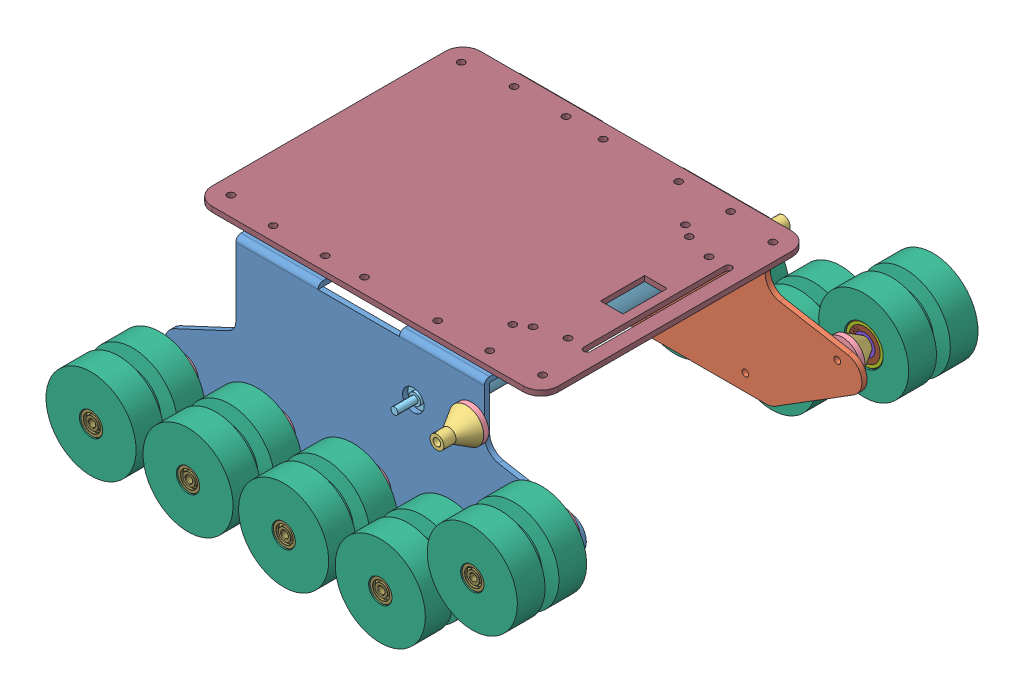
SolidWorks assembly Small_Robot_Assembly, configuration Default. Lengths in mm.
Overall size (294.99 123.27 269.5).
228 component instances, 13 part files, 42 mates.
Components (placement in the parent):
- Right_Side-1: Right_Side [Default] at (-96.7402 64.2453 5) size (240.5 93 16)
- Drivetrain_SubAssembly^Small_Robot_Assembly-1: Drivetrain_SubAssembly^Small_Robot_Assembly [Default] at origin size (288.98 120.27 124.55) (virtual)
  - Left_Side-1: Left_Side [Default] at (-96.7402 64.2453 -157.1) size (245.38 93 16)
  - Sprocket_Spacer-1: Sprocket_Spacer [Default] at (-131.6324 -16.2547 -160.1) x (0.139555 0.990214 0) z (0 0 -1) size (20 20 17)
  - Sprocket_Spacer_Simple-1: Sprocket_Spacer_Simple [Default] at (-131.6324 -16.2547 -157.1) x (0.943397 -0.331665 0) z (0.331665 0.943397 0) size (20 3 20)
  - Sprocket_Spacer_Simple-2: Sprocket_Spacer_Simple [Default] at (-75.6324 -16.2547 -157.1) x (0.978535 -0.206079 0) z (0.206079 0.978535 0) size (20 3 20)
  - Sprocket_Spacer-2: Sprocket_Spacer [Default] at (-75.6324 -16.2547 -160.1) x (0 1 0) z (0 0 -1) size (20 20 17)
  - Sprocket_Spacer-3: Sprocket_Spacer [Default] at (-20.4324 -16.2547 -160.1) x (0 1 0) z (0 0 -1) size (20 20 17)
  - Sprocket_Spacer_Simple-3: Sprocket_Spacer_Simple [Default] at (-20.4324 -16.2547 -157.1) x (0.680324 -0.732912 0) z (0.732912 0.680324 0) size (20 3 20)
  - Sprocket_Spacer_Simple-4: Sprocket_Spacer_Simple [Default] at (35.3676 -16.2547 -157.1) x (0.978535 -0.206079 0) z (0.206079 0.978535 0) size (20 3 20)
  - Sprocket_Spacer-4: Sprocket_Spacer [Default] at (35.3676 -16.2547 -160.1) x (0 1 0) z (0 0 -1) size (20 20 17)
  - Sprocket_Spacer_Simple-5: Sprocket_Spacer_Simple [Default] at (88.4881 16.6764 -157.1) x (0.978535 -0.206079 0) z (0.206079 0.978535 0) size (20 3 20)
  - Sprocket_Spacer-5: Sprocket_Spacer [Default] at (88.4881 16.6764 -160.1) x (0 1 0) z (0 0 -1) size (20 20 17)
  - Sprocket_Spacer-6: Sprocket_Spacer [Default] at (34.2676 46.7453 -160.1) x (0 1 0) z (0 0 -1) size (20 20 17)
  - Sprocket_Spacer_Simple-6: Sprocket_Spacer_Simple [Default] at (34.2676 46.7453 -157.1) x (0.978535 -0.206079 0) z (0.206079 0.978535 0) size (20 3 20)
  - Motor-1: Motor [Default] at (5.7598 36.4953 -84.75) x (-1 0 0) z (0 0 -1) size (26.5 26.5 83.25)
  - Runner_Wheel_Bearing_Assembly-1: Runner_Wheel_Bearing_Assembly [Default] at (80.6855 -26.7552 -161.7371) x (0.962373 0.271731 0) z (-0.271731 0.962373 0) size (52 40 52)
    - Runner_Wheel-1: Runner_Wheel [Default] at (19.3107 7.5629 39.6772) size (52 40 52)
    - Ball_Bearing_608_2RSH-1: Ball_Bearing_608_2RSH [Default] at (19.3107 11.5629 39.6772) x (0.810649 0 -0.585532) z (0.585532 0 0.810649) size (25.49 7.53 25.49)
      - Deep Groove Ball Bearing 608-2RSH 8mm I.D, 22mm O.D.stp-1: Deep Groove Ball Bearing 608-2RSH 8mm I.D, 22mm O.D.stp [Default] at origin size (25.49 7.53 25.49)
        - outer race.stp-1: outer race.stp [Default] at origin size (22 7 22)
        - inner race.stp-1: inner race.stp [Default] x (0.998045 0 -0.0625) z (0.0625 0 0.998045) size (12 7 12)
        - retainer.stp-1: retainer.stp [Default] x (-0.325178 0 -0.945653) z (-0.945653 0 0.325178) size (20.06 6 20.06)
        - ball.stp-1: ball.stp [Default] at (-6.7396 0 -3.2906) x (-0.584318 0.768334 -0.261218) z (-0.624567 -0.631294 -0.459765) size (5 5 5)
        - ball.stp-2: ball.stp [Default] at (3.2906 0 -6.7396) x (-0.938425 0.011388 -0.345297) z (0.106265 -0.94149 -0.319851) size (5 5 5)
        - ball.stp-3: ball.stp [Default] at (-2.4388 0 -7.0924) x (-0.938425 0.011388 -0.345297) z (0.106265 -0.94149 -0.319851) size (5 5 5)
        - ball.stp-4: ball.stp [Default] at (7.0924 0 -2.4388) x (-0.938425 0.011388 -0.345297) z (0.106265 -0.94149 -0.319851) size (5 5 5)
        - ball.stp-5: ball.stp [Default] at (-7.0924 0 2.4388) x (-0.938425 0.011388 -0.345297) z (0.106265 -0.94149 -0.319851) size (5 5 5)
        - ball.stp-6: ball.stp [Default] at (-3.2906 0 6.7396) x (-0.938425 0.011388 -0.345297) z (0.106265 -0.94149 -0.319851) size (5 5 5)
        - ball.stp-7: ball.stp [Default] at (2.4388 0 7.0924) x (-0.938425 0.011388 -0.345297) z (0.106265 -0.94149 -0.319851) size (5 5 5)
        - ball.stp-8: ball.stp [Default] at (6.7396 0 3.2906) x (-0.938425 0.011388 -0.345297) z (0.106265 -0.94149 -0.319851) size (5 5 5)
        - cover.stp-1: cover.stp [Default] at (0 -3.25 0) x (0.969563 0 0.244841) z (-0.244841 0 0.969563) size (18 0.57 18)
        - cover.stp-2: cover.stp [Default] at (0 3.25 0) x (-0.15753 0 -0.987514) z (-0.987514 0 0.15753) size (18 0.57 18)
    - 624_Bearing-1: 624_Bearing [Default] at (19.3107 42.0629 39.6772) x (0 -1 0) z (0 0 -1) size (5 13 13)
  - Runner_Wheel_Bearing_Assembly-2: Runner_Wheel_Bearing_Assembly [Default] at (52.7988 -56.7928 -161.7371) x (0.653164 0.757217 0) z (-0.757217 0.653164 0) size (52 40 52)
    - Runner_Wheel-1: Runner_Wheel [Default] at (19.3107 7.5629 39.6772) size (52 40 52)
    - Ball_Bearing_608_2RSH-1: Ball_Bearing_608_2RSH [Default] at (19.3107 11.5629 39.6772) x (0.810649 0 -0.585532) z (0.585532 0 0.810649) size (25.49 7.53 25.49)
      - Deep Groove Ball Bearing 608-2RSH 8mm I.D, 22mm O.D.stp-1: Deep Groove Ball Bearing 608-2RSH 8mm I.D, 22mm O.D.stp [Default] at origin size (25.49 7.53 25.49)
        - outer race.stp-1: outer race.stp [Default] at origin size (22 7 22)
        - inner race.stp-1: inner race.stp [Default] x (0.998045 0 -0.0625) z (0.0625 0 0.998045) size (12 7 12)
        - retainer.stp-1: retainer.stp [Default] x (-0.325178 0 -0.945653) z (-0.945653 0 0.325178) size (20.06 6 20.06)
        - ball.stp-1: ball.stp [Default] at (-6.7396 0 -3.2906) x (-0.584318 0.768334 -0.261218) z (-0.624567 -0.631294 -0.459765) size (5 5 5)
        - ball.stp-2: ball.stp [Default] at (3.2906 0 -6.7396) x (-0.938425 0.011388 -0.345297) z (0.106265 -0.94149 -0.319851) size (5 5 5)
        - ball.stp-3: ball.stp [Default] at (-2.4388 0 -7.0924) x (-0.938425 0.011388 -0.345297) z (0.106265 -0.94149 -0.319851) size (5 5 5)
        - ball.stp-4: ball.stp [Default] at (7.0924 0 -2.4388) x (-0.938425 0.011388 -0.345297) z (0.106265 -0.94149 -0.319851) size (5 5 5)
        - ball.stp-5: ball.stp [Default] at (-7.0924 0 2.4388) x (-0.938425 0.011388 -0.345297) z (0.106265 -0.94149 -0.319851) size (5 5 5)
        - ball.stp-6: ball.stp [Default] at (-3.2906 0 6.7396) x (-0.938425 0.011388 -0.345297) z (0.106265 -0.94149 -0.319851) size (5 5 5)
        - ball.stp-7: ball.stp [Default] at (2.4388 0 7.0924) x (-0.938425 0.011388 -0.345297) z (0.106265 -0.94149 -0.319851) size (5 5 5)
        - ball.stp-8: ball.stp [Default] at (6.7396 0 3.2906) x (-0.938425 0.011388 -0.345297) z (0.106265 -0.94149 -0.319851) size (5 5 5)
        - cover.stp-1: cover.stp [Default] at (0 -3.25 0) x (0.969563 0 0.244841) z (-0.244841 0 0.969563) size (18 0.57 18)
        - cover.stp-2: cover.stp [Default] at (0 3.25 0) x (-0.15753 0 -0.987514) z (-0.987514 0 0.15753) size (18 0.57 18)
    - 624_Bearing-1: 624_Bearing [Default] at (19.3107 42.0629 39.6772) x (0 -1 0) z (0 0 -1) size (5 13 13)
  - Runner_Wheel_Bearing_Assembly-3: Runner_Wheel_Bearing_Assembly [Default] at (-73.4318 -60.3268 -161.7371) x (0.876219 0.481914 0) z (-0.481914 0.876219 0) size (52 40 52)
    - Runner_Wheel-1: Runner_Wheel [Default] at (19.3107 7.5629 39.6772) size (52 40 52)
    - Ball_Bearing_608_2RSH-1: Ball_Bearing_608_2RSH [Default] at (19.3107 11.5629 39.6772) x (0.810649 0 -0.585532) z (0.585532 0 0.810649) size (25.49 7.53 25.49)
      - Deep Groove Ball Bearing 608-2RSH 8mm I.D, 22mm O.D.stp-1: Deep Groove Ball Bearing 608-2RSH 8mm I.D, 22mm O.D.stp [Default] at origin size (25.49 7.53 25.49)
        - outer race.stp-1: outer race.stp [Default] at origin size (22 7 22)
        - inner race.stp-1: inner race.stp [Default] x (0.998045 0 -0.0625) z (0.0625 0 0.998045) size (12 7 12)
        - retainer.stp-1: retainer.stp [Default] x (-0.325178 0 -0.945653) z (-0.945653 0 0.325178) size (20.06 6 20.06)
        - ball.stp-1: ball.stp [Default] at (-6.7396 0 -3.2906) x (-0.584318 0.768334 -0.261218) z (-0.624567 -0.631294 -0.459765) size (5 5 5)
        - ball.stp-2: ball.stp [Default] at (3.2906 0 -6.7396) x (-0.938425 0.011388 -0.345297) z (0.106265 -0.94149 -0.319851) size (5 5 5)
        - ball.stp-3: ball.stp [Default] at (-2.4388 0 -7.0924) x (-0.938425 0.011388 -0.345297) z (0.106265 -0.94149 -0.319851) size (5 5 5)
        - ball.stp-4: ball.stp [Default] at (7.0924 0 -2.4388) x (-0.938425 0.011388 -0.345297) z (0.106265 -0.94149 -0.319851) size (5 5 5)
        - ball.stp-5: ball.stp [Default] at (-7.0924 0 2.4388) x (-0.938425 0.011388 -0.345297) z (0.106265 -0.94149 -0.319851) size (5 5 5)
        - ball.stp-6: ball.stp [Default] at (-3.2906 0 6.7396) x (-0.938425 0.011388 -0.345297) z (0.106265 -0.94149 -0.319851) size (5 5 5)
        - ball.stp-7: ball.stp [Default] at (2.4388 0 7.0924) x (-0.938425 0.011388 -0.345297) z (0.106265 -0.94149 -0.319851) size (5 5 5)
        - ball.stp-8: ball.stp [Default] at (6.7396 0 3.2906) x (-0.938425 0.011388 -0.345297) z (0.106265 -0.94149 -0.319851) size (5 5 5)
        - cover.stp-1: cover.stp [Default] at (0 -3.25 0) x (0.969563 0 0.244841) z (-0.244841 0 0.969563) size (18 0.57 18)
        - cover.stp-2: cover.stp [Default] at (0 3.25 0) x (-0.15753 0 -0.987514) z (-0.987514 0 0.15753) size (18 0.57 18)
    - 624_Bearing-1: 624_Bearing [Default] at (19.3107 42.0629 39.6772) x (0 -1 0) z (0 0 -1) size (5 13 13)
  - Runner_Wheel_Bearing_Assembly-4: Runner_Wheel_Bearing_Assembly [Default] at (-117.0247 -57.8937 -161.7371) x (0.703596 0.7106 0) z (-0.7106 0.703596 0) size (52 40 52)
    - Runner_Wheel-1: Runner_Wheel [Default] at (19.3107 7.5629 39.6772) size (52 40 52)
    - Ball_Bearing_608_2RSH-1: Ball_Bearing_608_2RSH [Default] at (19.3107 11.5629 39.6772) x (0.810649 0 -0.585532) z (0.585532 0 0.810649) size (25.49 7.53 25.49)
      - Deep Groove Ball Bearing 608-2RSH 8mm I.D, 22mm O.D.stp-1: Deep Groove Ball Bearing 608-2RSH 8mm I.D, 22mm O.D.stp [Default] at origin size (25.49 7.53 25.49)
        - outer race.stp-1: outer race.stp [Default] at origin size (22 7 22)
        - inner race.stp-1: inner race.stp [Default] x (0.998045 0 -0.0625) z (0.0625 0 0.998045) size (12 7 12)
        - retainer.stp-1: retainer.stp [Default] x (-0.325178 0 -0.945653) z (-0.945653 0 0.325178) size (20.06 6 20.06)
        - ball.stp-1: ball.stp [Default] at (-6.7396 0 -3.2906) x (-0.584318 0.768334 -0.261218) z (-0.624567 -0.631294 -0.459765) size (5 5 5)
        - ball.stp-2: ball.stp [Default] at (3.2906 0 -6.7396) x (-0.938425 0.011388 -0.345297) z (0.106265 -0.94149 -0.319851) size (5 5 5)
        - ball.stp-3: ball.stp [Default] at (-2.4388 0 -7.0924) x (-0.938425 0.011388 -0.345297) z (0.106265 -0.94149 -0.319851) size (5 5 5)
        - ball.stp-4: ball.stp [Default] at (7.0924 0 -2.4388) x (-0.938425 0.011388 -0.345297) z (0.106265 -0.94149 -0.319851) size (5 5 5)
        - ball.stp-5: ball.stp [Default] at (-7.0924 0 2.4388) x (-0.938425 0.011388 -0.345297) z (0.106265 -0.94149 -0.319851) size (5 5 5)
        - ball.stp-6: ball.stp [Default] at (-3.2906 0 6.7396) x (-0.938425 0.011388 -0.345297) z (0.106265 -0.94149 -0.319851) size (5 5 5)
        - ball.stp-7: ball.stp [Default] at (2.4388 0 7.0924) x (-0.938425 0.011388 -0.345297) z (0.106265 -0.94149 -0.319851) size (5 5 5)
        - ball.stp-8: ball.stp [Default] at (6.7396 0 3.2906) x (-0.938425 0.011388 -0.345297) z (0.106265 -0.94149 -0.319851) size (5 5 5)
        - cover.stp-1: cover.stp [Default] at (0 -3.25 0) x (0.969563 0 0.244841) z (-0.244841 0 0.969563) size (18 0.57 18)
        - cover.stp-2: cover.stp [Default] at (0 3.25 0) x (-0.15753 0 -0.987514) z (-0.987514 0 0.15753) size (18 0.57 18)
    - 624_Bearing-1: 624_Bearing [Default] at (19.3107 42.0629 39.6772) x (0 -1 0) z (0 0 -1) size (5 13 13)
  - Runner_Wheel_Bearing_Assembly-5: Runner_Wheel_Bearing_Assembly [Default] at (-15.6748 -60.1244 -161.7371) x (0.846738 0.53201 0) z (-0.53201 0.846738 0) size (52 40 52)
    - Runner_Wheel-1: Runner_Wheel [Default] at (19.3107 7.5629 39.6772) size (52 40 52)
    - Ball_Bearing_608_2RSH-1: Ball_Bearing_608_2RSH [Default] at (19.3107 11.5629 39.6772) x (0.810649 0 -0.585532) z (0.585532 0 0.810649) size (25.49 7.53 25.49)
      - Deep Groove Ball Bearing 608-2RSH 8mm I.D, 22mm O.D.stp-1: Deep Groove Ball Bearing 608-2RSH 8mm I.D, 22mm O.D.stp [Default] at origin size (25.49 7.53 25.49)
        - outer race.stp-1: outer race.stp [Default] at origin size (22 7 22)
        - inner race.stp-1: inner race.stp [Default] x (0.998045 0 -0.0625) z (0.0625 0 0.998045) size (12 7 12)
        - retainer.stp-1: retainer.stp [Default] x (-0.325178 0 -0.945653) z (-0.945653 0 0.325178) size (20.06 6 20.06)
        - ball.stp-1: ball.stp [Default] at (-6.7396 0 -3.2906) x (-0.584318 0.768334 -0.261218) z (-0.624567 -0.631294 -0.459765) size (5 5 5)
        - ball.stp-2: ball.stp [Default] at (3.2906 0 -6.7396) x (-0.938425 0.011388 -0.345297) z (0.106265 -0.94149 -0.319851) size (5 5 5)
        - ball.stp-3: ball.stp [Default] at (-2.4388 0 -7.0924) x (-0.938425 0.011388 -0.345297) z (0.106265 -0.94149 -0.319851) size (5 5 5)
        - ball.stp-4: ball.stp [Default] at (7.0924 0 -2.4388) x (-0.938425 0.011388 -0.345297) z (0.106265 -0.94149 -0.319851) size (5 5 5)
        - ball.stp-5: ball.stp [Default] at (-7.0924 0 2.4388) x (-0.938425 0.011388 -0.345297) z (0.106265 -0.94149 -0.319851) size (5 5 5)
        - ball.stp-6: ball.stp [Default] at (-3.2906 0 6.7396) x (-0.938425 0.011388 -0.345297) z (0.106265 -0.94149 -0.319851) size (5 5 5)
        - ball.stp-7: ball.stp [Default] at (2.4388 0 7.0924) x (-0.938425 0.011388 -0.345297) z (0.106265 -0.94149 -0.319851) size (5 5 5)
        - ball.stp-8: ball.stp [Default] at (6.7396 0 3.2906) x (-0.938425 0.011388 -0.345297) z (0.106265 -0.94149 -0.319851) size (5 5 5)
        - cover.stp-1: cover.stp [Default] at (0 -3.25 0) x (0.969563 0 0.244841) z (-0.244841 0 0.969563) size (18 0.57 18)
        - cover.stp-2: cover.stp [Default] at (0 3.25 0) x (-0.15753 0 -0.987514) z (-0.987514 0 0.15753) size (18 0.57 18)
    - 624_Bearing-1: 624_Bearing [Default] at (19.3107 42.0629 39.6772) x (0 -1 0) z (0 0 -1) size (5 13 13)
- Top_Plate-1: Top_Plate [Default] at (74.3598 67.2453 -152.05) x (-1 0 0) z (0 0 -1) size (200 3 155)
- Motor-1: Motor [Default] at (5.7598 36.4953 -64.35) x (0.998113 -0.061402 0) z (0 0 1) size (26.5 26.5 83.25)
- Sprocket_Spacer_Simple-7: Sprocket_Spacer_Simple [Default] at (39.4002 42.2453 11) x (0.978535 -0.206079 0) z (0.206079 0.978535 0) size (20 3 20)
- Sprocket_Spacer_Simple-9: Sprocket_Spacer_Simple [Default] at (-72.0998 -16.2547 11) x (0.978535 -0.206079 0) z (0.206079 0.978535 0) size (20 3 20)
- Sprocket_Spacer_Simple-10: Sprocket_Spacer_Simple [Default] at (-16.8998 -16.2547 11) x (0.978535 -0.206079 0) z (0.206079 0.978535 0) size (20 3 20)
- Sprocket_Spacer_Simple-11: Sprocket_Spacer_Simple [Default] at (38.9002 -16.2547 11) x (0.978535 -0.206079 0) z (0.206079 0.978535 0) size (20 3 20)
- Sprocket_Spacer_Simple-12: Sprocket_Spacer_Simple [Default] at (92.0184 16.6802 11) x (0.978535 -0.206079 0) z (0.206079 0.978535 0) size (20 3 20)
- Sprocket_Spacer_Simple-14: Sprocket_Spacer_Simple [Default] at (-128.0998 -16.2547 11) x (0.944569 -0.328314 0) z (0.328314 0.944569 0) size (20 3 20)
- Sprocket_Spacer-8: Sprocket_Spacer [Default] at (-128.0998 -16.2547 11) x (0.992079 0.125614 0) z (0 0 1) size (20 20 17)
- Sprocket_Spacer-9: Sprocket_Spacer [Default] at (-72.0998 -16.2547 11) size (20 20 17)
- Sprocket_Spacer-10: Sprocket_Spacer [Default] at (-16.8998 -16.2547 11) size (20 20 17)
- Sprocket_Spacer-11: Sprocket_Spacer [Default] at (38.9002 -16.2547 11) size (20 20 17)
- Sprocket_Spacer-12: Sprocket_Spacer [Default] at (39.4002 42.2453 11) size (20 20 17)
- Sprocket_Spacer-13: Sprocket_Spacer [Default] at (92.0184 16.6802 11) size (20 20 17)
- Runner_Wheel_Bearing_Assembly-6: Runner_Wheel_Bearing_Assembly [Default] at (64.261 -17.6231 12.6371) x (-0.42371 0.905798 0) z (0.905798 0.42371 0) size (52 40 52)
  - Runner_Wheel-1: Runner_Wheel [Default] at (19.3107 7.5629 39.6772) size (52 40 52)
  - Ball_Bearing_608_2RSH-1: Ball_Bearing_608_2RSH [Default] at (19.3107 11.5629 39.6772) x (0.810649 0 -0.585532) z (0.585532 0 0.810649) size (25.49 7.53 25.49)
    - Deep Groove Ball Bearing 608-2RSH 8mm I.D, 22mm O.D.stp-1: Deep Groove Ball Bearing 608-2RSH 8mm I.D, 22mm O.D.stp [Default] at origin size (25.49 7.53 25.49)
      - outer race.stp-1: outer race.stp [Default] at origin size (22 7 22)
      - inner race.stp-1: inner race.stp [Default] x (0.998045 0 -0.0625) z (0.0625 0 0.998045) size (12 7 12)
      - retainer.stp-1: retainer.stp [Default] x (-0.325178 0 -0.945653) z (-0.945653 0 0.325178) size (20.06 6 20.06)
      - ball.stp-1: ball.stp [Default] at (-6.7396 0 -3.2906) x (-0.584318 0.768334 -0.261218) z (-0.624567 -0.631294 -0.459765) size (5 5 5)
      - ball.stp-2: ball.stp [Default] at (3.2906 0 -6.7396) x (-0.938425 0.011388 -0.345297) z (0.106265 -0.94149 -0.319851) size (5 5 5)
      - ball.stp-3: ball.stp [Default] at (-2.4388 0 -7.0924) x (-0.938425 0.011388 -0.345297) z (0.106265 -0.94149 -0.319851) size (5 5 5)
      - ball.stp-4: ball.stp [Default] at (7.0924 0 -2.4388) x (-0.938425 0.011388 -0.345297) z (0.106265 -0.94149 -0.319851) size (5 5 5)
      - ball.stp-5: ball.stp [Default] at (-7.0924 0 2.4388) x (-0.938425 0.011388 -0.345297) z (0.106265 -0.94149 -0.319851) size (5 5 5)
      - ball.stp-6: ball.stp [Default] at (-3.2906 0 6.7396) x (-0.938425 0.011388 -0.345297) z (0.106265 -0.94149 -0.319851) size (5 5 5)
      - ball.stp-7: ball.stp [Default] at (2.4388 0 7.0924) x (-0.938425 0.011388 -0.345297) z (0.106265 -0.94149 -0.319851) size (5 5 5)
      - ball.stp-8: ball.stp [Default] at (6.7396 0 3.2906) x (-0.938425 0.011388 -0.345297) z (0.106265 -0.94149 -0.319851) size (5 5 5)
      - cover.stp-1: cover.stp [Default] at (0 -3.25 0) x (0.969563 0 0.244841) z (-0.244841 0 0.969563) size (18 0.57 18)
      - cover.stp-2: cover.stp [Default] at (0 3.25 0) x (-0.15753 0 -0.987514) z (-0.987514 0 0.15753) size (18 0.57 18)
  - 624_Bearing-1: 624_Bearing [Default] at (19.3107 42.0629 39.6772) x (0 -1 0) z (0 0 -1) size (5 13 13)
- Runner_Wheel_Bearing_Assembly-7: Runner_Wheel_Bearing_Assembly [Default] at (-51.7989 -43.2592 12.6371) x (-0.20416 0.978938 0) z (0.978938 0.20416 0) size (52 40 52)
  - Runner_Wheel-1: Runner_Wheel [Default] at (19.3107 7.5629 39.6772) size (52 40 52)
  - Ball_Bearing_608_2RSH-1: Ball_Bearing_608_2RSH [Default] at (19.3107 11.5629 39.6772) x (0.810649 0 -0.585532) z (0.585532 0 0.810649) size (25.49 7.53 25.49)
    - Deep Groove Ball Bearing 608-2RSH 8mm I.D, 22mm O.D.stp-1: Deep Groove Ball Bearing 608-2RSH 8mm I.D, 22mm O.D.stp [Default] at origin size (25.49 7.53 25.49)
      - outer race.stp-1: outer race.stp [Default] at origin size (22 7 22)
      - inner race.stp-1: inner race.stp [Default] x (0.998045 0 -0.0625) z (0.0625 0 0.998045) size (12 7 12)
      - retainer.stp-1: retainer.stp [Default] x (-0.325178 0 -0.945653) z (-0.945653 0 0.325178) size (20.06 6 20.06)
      - ball.stp-1: ball.stp [Default] at (-6.7396 0 -3.2906) x (-0.584318 0.768334 -0.261218) z (-0.624567 -0.631294 -0.459765) size (5 5 5)
      - ball.stp-2: ball.stp [Default] at (3.2906 0 -6.7396) x (-0.938425 0.011388 -0.345297) z (0.106265 -0.94149 -0.319851) size (5 5 5)
      - ball.stp-3: ball.stp [Default] at (-2.4388 0 -7.0924) x (-0.938425 0.011388 -0.345297) z (0.106265 -0.94149 -0.319851) size (5 5 5)
      - ball.stp-4: ball.stp [Default] at (7.0924 0 -2.4388) x (-0.938425 0.011388 -0.345297) z (0.106265 -0.94149 -0.319851) size (5 5 5)
      - ball.stp-5: ball.stp [Default] at (-7.0924 0 2.4388) x (-0.938425 0.011388 -0.345297) z (0.106265 -0.94149 -0.319851) size (5 5 5)
      - ball.stp-6: ball.stp [Default] at (-3.2906 0 6.7396) x (-0.938425 0.011388 -0.345297) z (0.106265 -0.94149 -0.319851) size (5 5 5)
      - ball.stp-7: ball.stp [Default] at (2.4388 0 7.0924) x (-0.938425 0.011388 -0.345297) z (0.106265 -0.94149 -0.319851) size (5 5 5)
      - ball.stp-8: ball.stp [Default] at (6.7396 0 3.2906) x (-0.938425 0.011388 -0.345297) z (0.106265 -0.94149 -0.319851) size (5 5 5)
      - cover.stp-1: cover.stp [Default] at (0 -3.25 0) x (0.969563 0 0.244841) z (-0.244841 0 0.969563) size (18 0.57 18)
      - cover.stp-2: cover.stp [Default] at (0 3.25 0) x (-0.15753 0 -0.987514) z (-0.987514 0 0.15753) size (18 0.57 18)
  - 624_Bearing-1: 624_Bearing [Default] at (19.3107 42.0629 39.6772) x (0 -1 0) z (0 0 -1) size (5 13 13)
- Runner_Wheel_Bearing_Assembly-8: Runner_Wheel_Bearing_Assembly [Default] at (-109.398 -39.8351 12.6371) x (-0.110595 0.993866 0) z (0.993866 0.110595 0) size (52 40 52)
  - Runner_Wheel-1: Runner_Wheel [Default] at (19.3107 7.5629 39.6772) size (52 40 52)
  - Ball_Bearing_608_2RSH-1: Ball_Bearing_608_2RSH [Default] at (19.3107 11.5629 39.6772) x (0.810649 0 -0.585532) z (0.585532 0 0.810649) size (25.49 7.53 25.49)
    - Deep Groove Ball Bearing 608-2RSH 8mm I.D, 22mm O.D.stp-1: Deep Groove Ball Bearing 608-2RSH 8mm I.D, 22mm O.D.stp [Default] at origin size (25.49 7.53 25.49)
      - outer race.stp-1: outer race.stp [Default] at origin size (22 7 22)
      - inner race.stp-1: inner race.stp [Default] x (0.998045 0 -0.0625) z (0.0625 0 0.998045) size (12 7 12)
      - retainer.stp-1: retainer.stp [Default] x (-0.325178 0 -0.945653) z (-0.945653 0 0.325178) size (20.06 6 20.06)
      - ball.stp-1: ball.stp [Default] at (-6.7396 0 -3.2906) x (-0.584318 0.768334 -0.261218) z (-0.624567 -0.631294 -0.459765) size (5 5 5)
      - ball.stp-2: ball.stp [Default] at (3.2906 0 -6.7396) x (-0.938425 0.011388 -0.345297) z (0.106265 -0.94149 -0.319851) size (5 5 5)
      - ball.stp-3: ball.stp [Default] at (-2.4388 0 -7.0924) x (-0.938425 0.011388 -0.345297) z (0.106265 -0.94149 -0.319851) size (5 5 5)
      - ball.stp-4: ball.stp [Default] at (7.0924 0 -2.4388) x (-0.938425 0.011388 -0.345297) z (0.106265 -0.94149 -0.319851) size (5 5 5)
      - ball.stp-5: ball.stp [Default] at (-7.0924 0 2.4388) x (-0.938425 0.011388 -0.345297) z (0.106265 -0.94149 -0.319851) size (5 5 5)
      - ball.stp-6: ball.stp [Default] at (-3.2906 0 6.7396) x (-0.938425 0.011388 -0.345297) z (0.106265 -0.94149 -0.319851) size (5 5 5)
      - ball.stp-7: ball.stp [Default] at (2.4388 0 7.0924) x (-0.938425 0.011388 -0.345297) z (0.106265 -0.94149 -0.319851) size (5 5 5)
      - ball.stp-8: ball.stp [Default] at (6.7396 0 3.2906) x (-0.938425 0.011388 -0.345297) z (0.106265 -0.94149 -0.319851) size (5 5 5)
      - cover.stp-1: cover.stp [Default] at (0 -3.25 0) x (0.969563 0 0.244841) z (-0.244841 0 0.969563) size (18 0.57 18)
      - cover.stp-2: cover.stp [Default] at (0 3.25 0) x (-0.15753 0 -0.987514) z (-0.987514 0 0.15753) size (18 0.57 18)
  - 624_Bearing-1: 624_Bearing [Default] at (19.3107 42.0629 39.6772) x (0 -1 0) z (0 0 -1) size (5 13 13)
- Runner_Wheel_Bearing_Assembly-9: Runner_Wheel_Bearing_Assembly [Default] at (64.261 -17.6231 12.6371) x (-0.42371 0.905798 0) z (0.905798 0.42371 0) size (52 40 52)
  - Runner_Wheel-1: Runner_Wheel [Default] at (19.3107 7.5629 39.6772) size (52 40 52)
  - Ball_Bearing_608_2RSH-1: Ball_Bearing_608_2RSH [Default] at (19.3107 11.5629 39.6772) x (0.810649 0 -0.585532) z (0.585532 0 0.810649) size (25.49 7.53 25.49)
    - Deep Groove Ball Bearing 608-2RSH 8mm I.D, 22mm O.D.stp-1: Deep Groove Ball Bearing 608-2RSH 8mm I.D, 22mm O.D.stp [Default] at origin size (25.49 7.53 25.49)
      - outer race.stp-1: outer race.stp [Default] at origin size (22 7 22)
      - inner race.stp-1: inner race.stp [Default] x (0.998045 0 -0.0625) z (0.0625 0 0.998045) size (12 7 12)
      - retainer.stp-1: retainer.stp [Default] x (-0.325178 0 -0.945653) z (-0.945653 0 0.325178) size (20.06 6 20.06)
      - ball.stp-1: ball.stp [Default] at (-6.7396 0 -3.2906) x (-0.584318 0.768334 -0.261218) z (-0.624567 -0.631294 -0.459765) size (5 5 5)
      - ball.stp-2: ball.stp [Default] at (3.2906 0 -6.7396) x (-0.938425 0.011388 -0.345297) z (0.106265 -0.94149 -0.319851) size (5 5 5)
      - ball.stp-3: ball.stp [Default] at (-2.4388 0 -7.0924) x (-0.938425 0.011388 -0.345297) z (0.106265 -0.94149 -0.319851) size (5 5 5)
      - ball.stp-4: ball.stp [Default] at (7.0924 0 -2.4388) x (-0.938425 0.011388 -0.345297) z (0.106265 -0.94149 -0.319851) size (5 5 5)
      - ball.stp-5: ball.stp [Default] at (-7.0924 0 2.4388) x (-0.938425 0.011388 -0.345297) z (0.106265 -0.94149 -0.319851) size (5 5 5)
      - ball.stp-6: ball.stp [Default] at (-3.2906 0 6.7396) x (-0.938425 0.011388 -0.345297) z (0.106265 -0.94149 -0.319851) size (5 5 5)
      - ball.stp-7: ball.stp [Default] at (2.4388 0 7.0924) x (-0.938425 0.011388 -0.345297) z (0.106265 -0.94149 -0.319851) size (5 5 5)
      - ball.stp-8: ball.stp [Default] at (6.7396 0 3.2906) x (-0.938425 0.011388 -0.345297) z (0.106265 -0.94149 -0.319851) size (5 5 5)
      - cover.stp-1: cover.stp [Default] at (0 -3.25 0) x (0.969563 0 0.244841) z (-0.244841 0 0.969563) size (18 0.57 18)
      - cover.stp-2: cover.stp [Default] at (0 3.25 0) x (-0.15753 0 -0.987514) z (-0.987514 0 0.15753) size (18 0.57 18)
  - 624_Bearing-1: 624_Bearing [Default] at (19.3107 42.0629 39.6772) x (0 -1 0) z (0 0 -1) size (5 13 13)
- Runner_Wheel_Bearing_Assembly-10: Runner_Wheel_Bearing_Assembly [Default] at (-164.8682 -40.6529 12.6371) x (-0.132513 0.991181 0) z (0.991181 0.132513 0) size (52 40 52)
  - Runner_Wheel-1: Runner_Wheel [Default] at (19.3107 7.5629 39.6772) size (52 40 52)
  - Ball_Bearing_608_2RSH-1: Ball_Bearing_608_2RSH [Default] at (19.3107 11.5629 39.6772) x (0.810649 0 -0.585532) z (0.585532 0 0.810649) size (25.49 7.53 25.49)
    - Deep Groove Ball Bearing 608-2RSH 8mm I.D, 22mm O.D.stp-1: Deep Groove Ball Bearing 608-2RSH 8mm I.D, 22mm O.D.stp [Default] at origin size (25.49 7.53 25.49)
      - outer race.stp-1: outer race.stp [Default] at origin size (22 7 22)
      - inner race.stp-1: inner race.stp [Default] x (0.998045 0 -0.0625) z (0.0625 0 0.998045) size (12 7 12)
      - retainer.stp-1: retainer.stp [Default] x (-0.325178 0 -0.945653) z (-0.945653 0 0.325178) size (20.06 6 20.06)
      - ball.stp-1: ball.stp [Default] at (-6.7396 0 -3.2906) x (-0.584318 0.768334 -0.261218) z (-0.624567 -0.631294 -0.459765) size (5 5 5)
      - ball.stp-2: ball.stp [Default] at (3.2906 0 -6.7396) x (-0.938425 0.011388 -0.345297) z (0.106265 -0.94149 -0.319851) size (5 5 5)
      - ball.stp-3: ball.stp [Default] at (-2.4388 0 -7.0924) x (-0.938425 0.011388 -0.345297) z (0.106265 -0.94149 -0.319851) size (5 5 5)
      - ball.stp-4: ball.stp [Default] at (7.0924 0 -2.4388) x (-0.938425 0.011388 -0.345297) z (0.106265 -0.94149 -0.319851) size (5 5 5)
      - ball.stp-5: ball.stp [Default] at (-7.0924 0 2.4388) x (-0.938425 0.011388 -0.345297) z (0.106265 -0.94149 -0.319851) size (5 5 5)
      - ball.stp-6: ball.stp [Default] at (-3.2906 0 6.7396) x (-0.938425 0.011388 -0.345297) z (0.106265 -0.94149 -0.319851) size (5 5 5)
      - ball.stp-7: ball.stp [Default] at (2.4388 0 7.0924) x (-0.938425 0.011388 -0.345297) z (0.106265 -0.94149 -0.319851) size (5 5 5)
      - ball.stp-8: ball.stp [Default] at (6.7396 0 3.2906) x (-0.938425 0.011388 -0.345297) z (0.106265 -0.94149 -0.319851) size (5 5 5)
      - cover.stp-1: cover.stp [Default] at (0 -3.25 0) x (0.969563 0 0.244841) z (-0.244841 0 0.969563) size (18 0.57 18)
      - cover.stp-2: cover.stp [Default] at (0 3.25 0) x (-0.15753 0 -0.987514) z (-0.987514 0 0.15753) size (18 0.57 18)
  - 624_Bearing-1: 624_Bearing [Default] at (19.3107 42.0629 39.6772) x (0 -1 0) z (0 0 -1) size (5 13 13)
- Runner_Wheel_Bearing_Assembly-11: Runner_Wheel_Bearing_Assembly [Default] at (-4.5644 -8.6379 12.6371) x (0.586255 0.810127 0) z (0.810127 -0.586255 0) size (52 40 52)
  - Runner_Wheel-1: Runner_Wheel [Default] at (19.3107 7.5629 39.6772) size (52 40 52)
  - Ball_Bearing_608_2RSH-1: Ball_Bearing_608_2RSH [Default] at (19.3107 11.5629 39.6772) x (0.810649 0 -0.585532) z (0.585532 0 0.810649) size (25.49 7.53 25.49)
    - Deep Groove Ball Bearing 608-2RSH 8mm I.D, 22mm O.D.stp-1: Deep Groove Ball Bearing 608-2RSH 8mm I.D, 22mm O.D.stp [Default] at origin size (25.49 7.53 25.49)
      - outer race.stp-1: outer race.stp [Default] at origin size (22 7 22)
      - inner race.stp-1: inner race.stp [Default] x (0.998045 0 -0.0625) z (0.0625 0 0.998045) size (12 7 12)
      - retainer.stp-1: retainer.stp [Default] x (-0.325178 0 -0.945653) z (-0.945653 0 0.325178) size (20.06 6 20.06)
      - ball.stp-1: ball.stp [Default] at (-6.7396 0 -3.2906) x (-0.584318 0.768334 -0.261218) z (-0.624567 -0.631294 -0.459765) size (5 5 5)
      - ball.stp-2: ball.stp [Default] at (3.2906 0 -6.7396) x (-0.938425 0.011388 -0.345297) z (0.106265 -0.94149 -0.319851) size (5 5 5)
      - ball.stp-3: ball.stp [Default] at (-2.4388 0 -7.0924) x (-0.938425 0.011388 -0.345297) z (0.106265 -0.94149 -0.319851) size (5 5 5)
      - ball.stp-4: ball.stp [Default] at (7.0924 0 -2.4388) x (-0.938425 0.011388 -0.345297) z (0.106265 -0.94149 -0.319851) size (5 5 5)
      - ball.stp-5: ball.stp [Default] at (-7.0924 0 2.4388) x (-0.938425 0.011388 -0.345297) z (0.106265 -0.94149 -0.319851) size (5 5 5)
      - ball.stp-6: ball.stp [Default] at (-3.2906 0 6.7396) x (-0.938425 0.011388 -0.345297) z (0.106265 -0.94149 -0.319851) size (5 5 5)
      - ball.stp-7: ball.stp [Default] at (2.4388 0 7.0924) x (-0.938425 0.011388 -0.345297) z (0.106265 -0.94149 -0.319851) size (5 5 5)
      - ball.stp-8: ball.stp [Default] at (6.7396 0 3.2906) x (-0.938425 0.011388 -0.345297) z (0.106265 -0.94149 -0.319851) size (5 5 5)
      - cover.stp-1: cover.stp [Default] at (0 -3.25 0) x (0.969563 0 0.244841) z (-0.244841 0 0.969563) size (18 0.57 18)
      - cover.stp-2: cover.stp [Default] at (0 3.25 0) x (-0.15753 0 -0.987514) z (-0.987514 0 0.15753) size (18 0.57 18)
  - 624_Bearing-1: 624_Bearing [Default] at (19.3107 42.0629 39.6772) x (0 -1 0) z (0 0 -1) size (5 13 13)
Mates (geometry in assembly coordinates):
- Concentric1: concentric aligned: cylinder of Right_Side-1 through (36.8598 -25.7547 -5) axis (0 1 0) radius 1.9; cylinder of Top_Plate-1 through (36.8598 67.2453 -5) axis (0 1 0) radius 2.05
- Parallel1: parallel aligned: plane of Right_Side-1 through (-103.7621 24.2453 8) normal (0 0 1); plane of Top_Plate-1 through (74.3598 70.2453 2.95) normal (0 0 1)
- Coincident2: coincident anti-aligned: plane of Right_Side-1 through (-113.0191 67.2453 5) normal (0 1 0); plane of Top_Plate-1 through (74.3598 67.2453 -152.05) normal (0 -1 0)
- Concentric3: concentric anti-aligned: cylinder of Right_Side-1 through (5.7598 36.4953 5) axis (0 0 1) radius 6.25; cylinder of Motor-1 through (5.7598 36.4953 18.9) axis (0 0 -1) radius 2
- Coincident5: coincident anti-aligned: plane of Right_Side-1 through (-103.7621 24.2453 5) normal (0 0 -1); plane of Motor-1 through (5.7598 36.4953 5) normal (0 0 1)
- Concentric17: concentric aligned: cylinder of Right_Side-1 through (39.4002 42.2453 5) axis (0 0 1) radius 1.9; cylinder of Sprocket_Spacer_Simple-7 through (39.4002 42.2453 8) axis (0 0 1) radius 2.25
- Concentric18: concentric aligned: cylinder of Right_Side-1 through (92.0184 16.6802 5) axis (0 0 1) radius 1.9; cylinder of Sprocket_Spacer_Simple-12 through (92.0184 16.6802 8) axis (0 0 1) radius 2.25
- Concentric19: concentric aligned: cylinder of Right_Side-1 through (38.9002 -16.2547 5) axis (0 0 1) radius 1.9; cylinder of Sprocket_Spacer_Simple-11 through (38.9002 -16.2547 8) axis (0 0 1) radius 2.25
- Concentric20: concentric aligned: cylinder of Right_Side-1 through (-16.8998 -16.2547 5) axis (0 0 1) radius 1.9; cylinder of Sprocket_Spacer_Simple-10 through (-16.8998 -16.2547 8) axis (0 0 1) radius 2.25
- Concentric21: concentric aligned: cylinder of Right_Side-1 through (-72.0998 -16.2547 5) axis (0 0 1) radius 1.9; cylinder of Sprocket_Spacer_Simple-9 through (-72.0998 -16.2547 8) axis (0 0 1) radius 2.25
- Coincident23: coincident anti-aligned: circle of Right_Side-1; circle of Sprocket_Spacer_Simple-7
- Coincident24: coincident anti-aligned: plane of Right_Side-1 through (-103.7621 24.2453 8) normal (0 0 1); plane of Sprocket_Spacer_Simple-9 through (-72.0998 -16.2547 8) normal (0 0 -1)
- Coincident25: coincident anti-aligned: plane of Right_Side-1 through (-103.7621 24.2453 8) normal (0 0 1); plane of Sprocket_Spacer_Simple-10 through (-16.8998 -16.2547 8) normal (0 0 -1)
- Coincident26: coincident anti-aligned: plane of Right_Side-1 through (-103.7621 24.2453 8) normal (0 0 1); plane of Sprocket_Spacer_Simple-12 through (92.0184 16.6802 8) normal (0 0 -1)
- Coincident27: coincident anti-aligned: plane of Right_Side-1 through (-103.7621 24.2453 8) normal (0 0 1); plane of Sprocket_Spacer_Simple-11 through (38.9002 -16.2547 8) normal (0 0 -1)
- Slot1: slot aligned: cylinder of Right_Side-1 through (-125.3748 -16.2547 5) axis (0 0 1) radius 1.9; cylinder of Sprocket_Spacer_Simple-14 through (-128.0998 -16.2547 8) axis (0 0 1) radius 2.25; cylinder of Right_Side-1 through (-130.8248 -16.2547 5) axis (0 0 1) radius 1.9
- Coincident29: coincident anti-aligned: plane of Right_Side-1 through (-103.7621 24.2453 8) normal (0 0 1); plane of Sprocket_Spacer_Simple-14 through (-128.0998 -16.2547 8) normal (0 0 -1)
- Concentric22: concentric aligned: cylinder of Sprocket_Spacer_Simple-14 through (-128.0998 -16.2547 8) axis (0 0 1) radius 2.25; cylinder of Sprocket_Spacer-8 through (-128.0998 -16.2547 11) axis (0 0 1) radius 2.2
- Concentric23: concentric aligned: cylinder of Sprocket_Spacer_Simple-9 through (-72.0998 -16.2547 8) axis (0 0 1) radius 2.25; cylinder of Sprocket_Spacer-9 through (-72.0998 -16.2547 11) axis (0 0 1) radius 2.2
- Concentric24: concentric aligned: cylinder of Sprocket_Spacer_Simple-10 through (-16.8998 -16.2547 8) axis (0 0 1) radius 2.25; cylinder of Sprocket_Spacer-10 through (-16.8998 -16.2547 11) axis (0 0 1) radius 2.2
- Concentric25: concentric aligned: cylinder of Sprocket_Spacer_Simple-11 through (38.9002 -16.2547 8) axis (0 0 1) radius 2.25; cylinder of Sprocket_Spacer-11 through (38.9002 -16.2547 11) axis (0 0 1) radius 2.2
- Concentric26: concentric aligned: cylinder of Sprocket_Spacer_Simple-7 through (39.4002 42.2453 8) axis (0 0 1) radius 2.25; cylinder of Sprocket_Spacer-12 through (39.4002 42.2453 11) axis (0 0 1) radius 2.2
- Concentric27: concentric aligned: cylinder of Sprocket_Spacer_Simple-12 through (92.0184 16.6802 8) axis (0 0 1) radius 2.25; cylinder of Sprocket_Spacer-13 through (92.0184 16.6802 11) axis (0 0 1) radius 2.2
- Coincident31: coincident anti-aligned: plane of Sprocket_Spacer_Simple-14 through (-128.0998 -16.2547 11) normal (0 0 1); plane of Sprocket_Spacer-8 through (-128.0998 -16.2547 11) normal (0 0 -1)
- Coincident32: coincident anti-aligned: plane of Sprocket_Spacer_Simple-9 through (-72.0998 -16.2547 11) normal (0 0 1); plane of Sprocket_Spacer-9 through (-72.0998 -16.2547 11) normal (0 0 -1)
- Coincident33: coincident anti-aligned: plane of Sprocket_Spacer_Simple-10 through (-16.8998 -16.2547 11) normal (0 0 1); plane of Sprocket_Spacer-10 through (-16.8998 -16.2547 11) normal (0 0 -1)
- Coincident34: coincident anti-aligned: plane of Sprocket_Spacer_Simple-11 through (38.9002 -16.2547 11) normal (0 0 1); plane of Sprocket_Spacer-11 through (38.9002 -16.2547 11) normal (0 0 -1)
- Coincident35: coincident anti-aligned: plane of Sprocket_Spacer_Simple-12 through (92.0184 16.6802 11) normal (0 0 1); plane of Sprocket_Spacer-13 through (92.0184 16.6802 11) normal (0 0 -1)
- Coincident36: coincident anti-aligned: plane of Sprocket_Spacer_Simple-7 through (39.4002 42.2453 11) normal (0 0 1); plane of Sprocket_Spacer-12 through (39.4002 42.2453 11) normal (0 0 -1)
- Concentric36: concentric aligned: cylinder of Sprocket_Spacer-13 through (92.0184 16.6802 11) axis (0 0 1) radius 2.2; cylinder of Runner_Wheel_Bearing_Assembly-6/Runner_Wheel-1 through (92.0184 16.6802 20.2) axis (0 0 1) radius 2
- Coincident42: coincident anti-aligned: cone of Sprocket_Spacer-13 through (92.0184 16.6802 21) axis (0 0 1); circle of Runner_Wheel_Bearing_Assembly-6/Ball_Bearing_608_2RSH-1/Deep Groove Ball Bearing 608-2RSH 8mm I.D, 22mm O.D.stp-1/inner race.stp-1
- Concentric37: concentric aligned: cylinder of Sprocket_Spacer-11 through (38.9002 -16.2547 11) axis (0 0 1) radius 2.2; cylinder of Runner_Wheel_Bearing_Assembly-11/Runner_Wheel-1 through (38.9002 -16.2547 20.2) axis (0 0 1) radius 2
- Concentric38: concentric aligned: cylinder of Sprocket_Spacer-10 through (-16.8998 -16.2547 11) axis (0 0 1) radius 2.2; cylinder of Runner_Wheel_Bearing_Assembly-7/Runner_Wheel-1 through (-16.8998 -16.2547 20.2) axis (0 0 1) radius 2
- Concentric39: concentric aligned: cylinder of Sprocket_Spacer-9 through (-72.0998 -16.2547 11) axis (0 0 1) radius 2.2; cylinder of Runner_Wheel_Bearing_Assembly-8/Runner_Wheel-1 through (-72.0998 -16.2547 20.2) axis (0 0 1) radius 2
- Concentric40: concentric aligned: cylinder of Sprocket_Spacer-8 through (-128.0998 -16.2547 11) axis (0 0 1) radius 2.2; cylinder of Runner_Wheel_Bearing_Assembly-10/Runner_Wheel-1 through (-128.0998 -16.2547 20.2) axis (0 0 1) radius 2
- Coincident43: coincident anti-aligned: cylinder of Sprocket_Spacer-11 through (38.9002 -16.2547 21) axis (0 0 1) radius 540.4195; circle of Runner_Wheel_Bearing_Assembly-11/Ball_Bearing_608_2RSH-1/Deep Groove Ball Bearing 608-2RSH 8mm I.D, 22mm O.D.stp-1/inner race.stp-1
- Coincident44: coincident anti-aligned: cylinder of Sprocket_Spacer-10 through (-16.8998 -16.2547 21) axis (0 0 1) radius 540.4195; circle of Runner_Wheel_Bearing_Assembly-7/Ball_Bearing_608_2RSH-1/Deep Groove Ball Bearing 608-2RSH 8mm I.D, 22mm O.D.stp-1/inner race.stp-1
- Coincident45: coincident anti-aligned: cylinder of Sprocket_Spacer-9 through (-72.0998 -16.2547 21) axis (0 0 1) radius 540.4195; circle of Runner_Wheel_Bearing_Assembly-8/Ball_Bearing_608_2RSH-1/Deep Groove Ball Bearing 608-2RSH 8mm I.D, 22mm O.D.stp-1/inner race.stp-1
- Coincident46: coincident anti-aligned: cylinder of Sprocket_Spacer-8 through (-128.0998 -16.2547 21) axis (0 0 1) radius 540.4195; circle of Runner_Wheel_Bearing_Assembly-10/Ball_Bearing_608_2RSH-1/Deep Groove Ball Bearing 608-2RSH 8mm I.D, 22mm O.D.stp-1/inner race.stp-1
- Concentric41: concentric aligned: cylinder of Assem1^Small_Robot_Assembly-1/Left_Side-1 through (36.8598 -25.7547 -144.1) axis (0 1 0) radius 1.9; cylinder of Top_Plate-1 through (36.8598 67.2453 -144.1) axis (0 1 0) radius 2.05
- Parallel3: parallel aligned: plane of Assem1^Small_Robot_Assembly-1/Left_Side-1 through (-100.188 24.2453 -157.1) normal (0 0 -1); plane of Top_Plate-1 through (74.3598 70.2453 -152.05) normal (0 0 -1)
- Coincident47: coincident anti-aligned: plane of Assem1^Small_Robot_Assembly-1/Left_Side-1 through (-113.0191 67.2453 -157.1) normal (0 1 0); plane of Top_Plate-1 through (74.3598 67.2453 -152.05) normal (0 -1 0)
